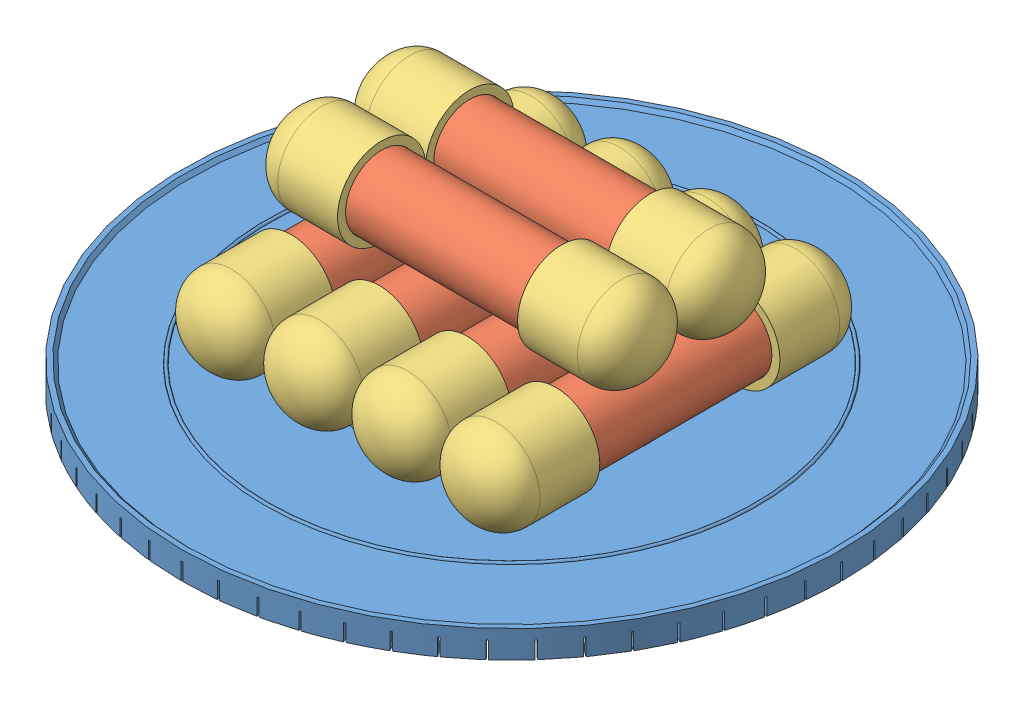
SolidWorks assembly OIL MAT AND SAMPLES, configuration Default. Lengths in mm.
Overall size (307.98 89.57 307.98).
25 component instances, 3 part files, 18 mates.
Components (placement in the parent):
- 5 GALLON LID-1: 5 GALLON LID [Default] at (-59.5528 148.0836 251.4971) size (307.98 12.7 307.98)
- OIL SAMPLE-1: OIL SAMPLE [Default] at (-23.8359 105.1502 145.4945) size (41.17 41.17 172.16)
  - 1 PVC PIPE 14CM-1: 1 PVC PIPE 14CM [48925K93] at (55.8359 74.6326 104.5055) size (33.4 33.4 140)
  - 1 PVC CAP-1: 1 PVC CAP [4880K53] at (55.8359 74.6326 168.5746) x (0 0 1) z (-1 0 0) size (44.02 41.17 41.17)
  - 1 PVC CAP-2: 1 PVC CAP [4880K53] at (55.8359 74.6326 40.4364) x (0 0 -1) z (1 0 0) size (44.02 41.17 41.17)
- OIL SAMPLE-2: OIL SAMPLE [Default] at (17.3375 105.1502 145.4945) size (41.17 41.17 172.16)
  - 1 PVC PIPE 14CM-1: 1 PVC PIPE 14CM [48925K93] at (55.8359 74.6326 104.5055) size (33.4 33.4 140)
  - 1 PVC CAP-1: 1 PVC CAP [4880K53] at (55.8359 74.6326 168.5746) x (0 0 1) z (-1 0 0) size (44.02 41.17 41.17)
  - 1 PVC CAP-2: 1 PVC CAP [4880K53] at (55.8359 74.6326 40.4364) x (0 0 -1) z (1 0 0) size (44.02 41.17 41.17)
- OIL SAMPLE-3: OIL SAMPLE [Default] at (58.5109 105.1502 145.4945) size (41.17 41.17 172.16)
  - 1 PVC PIPE 14CM-1: 1 PVC PIPE 14CM [48925K93] at (55.8359 74.6326 104.5055) size (33.4 33.4 140)
  - 1 PVC CAP-1: 1 PVC CAP [4880K53] at (55.8359 74.6326 168.5746) x (0 0 1) z (-1 0 0) size (44.02 41.17 41.17)
  - 1 PVC CAP-2: 1 PVC CAP [4880K53] at (55.8359 74.6326 40.4364) x (0 0 -1) z (1 0 0) size (44.02 41.17 41.17)
- OIL SAMPLE-4: OIL SAMPLE [Default] at (99.6843 105.1502 145.4945) size (41.17 41.17 172.16)
  - 1 PVC PIPE 14CM-1: 1 PVC PIPE 14CM [48925K93] at (55.8359 74.6326 104.5055) size (33.4 33.4 140)
  - 1 PVC CAP-1: 1 PVC CAP [4880K53] at (55.8359 74.6326 168.5746) x (0 0 1) z (-1 0 0) size (44.02 41.17 41.17)
  - 1 PVC CAP-2: 1 PVC CAP [4880K53] at (55.8359 74.6326 40.4364) x (0 0 -1) z (1 0 0) size (44.02 41.17 41.17)
- OIL SAMPLE-5: OIL SAMPLE [Default] at (-10 142.4374 326.1734) x (0 0 -1) z (1 0 0) size (41.17 41.17 172.16)
  - 1 PVC PIPE 14CM-1: 1 PVC PIPE 14CM [48925K93] at (55.8359 74.6326 104.5055) size (33.4 33.4 140)
  - 1 PVC CAP-1: 1 PVC CAP [4880K53] at (55.8359 74.6326 168.5746) x (0 0 1) z (-1 0 0) size (44.02 41.17 41.17)
  - 1 PVC CAP-2: 1 PVC CAP [4880K53] at (55.8359 74.6326 40.4364) x (0 0 -1) z (1 0 0) size (44.02 41.17 41.17)
- OIL SAMPLE-6: OIL SAMPLE [Default] at (-10 142.4374 285) x (0 0 -1) z (1 0 0) size (41.17 41.17 172.16)
  - 1 PVC PIPE 14CM-1: 1 PVC PIPE 14CM [48925K93] at (55.8359 74.6326 104.5055) size (33.4 33.4 140)
  - 1 PVC CAP-1: 1 PVC CAP [4880K53] at (55.8359 74.6326 168.5746) x (0 0 1) z (-1 0 0) size (44.02 41.17 41.17)
  - 1 PVC CAP-2: 1 PVC CAP [4880K53] at (55.8359 74.6326 40.4364) x (0 0 -1) z (1 0 0) size (44.02 41.17 41.17)
Mates (geometry in assembly coordinates):
- Coincident2: coincident aligned: plane of OIL SAMPLE-1 through (-23.8359 105.1502 145.4945) normal (0 1 0); plane of OIL SAMPLE-2 through (17.3375 105.1502 145.4945) normal (0 1 0)
- Coincident3: coincident aligned: plane of OIL SAMPLE-1 through (-23.8359 105.1502 145.4945) normal (0 1 0); plane of OIL SAMPLE-3 through (58.5109 105.1502 145.4945) normal (0 1 0)
- Coincident4: coincident aligned: plane of OIL SAMPLE-1 through (-23.8359 105.1502 145.4945) normal (0 1 0); plane of OIL SAMPLE-4 through (99.6843 105.1502 145.4945) normal (0 1 0)
- Coincident5: coincident aligned: plane of OIL SAMPLE-1 through (-23.8359 105.1502 145.4945) normal (0 0 1); plane of OIL SAMPLE-2 through (17.3375 105.1502 145.4945) normal (0 0 1)
- Coincident6: coincident aligned: plane of OIL SAMPLE-1 through (-23.8359 105.1502 145.4945) normal (0 0 1); plane of OIL SAMPLE-3 through (58.5109 105.1502 145.4945) normal (0 0 1)
- Coincident7: coincident aligned: plane of OIL SAMPLE-1 through (-23.8359 105.1502 145.4945) normal (0 0 1); plane of OIL SAMPLE-4 through (99.6843 105.1502 145.4945) normal (0 0 1)
- Tangent1: tangent anti-aligned: cylinder of OIL SAMPLE-1/1 PVC CAP-1 through (32 179.7828 292.06) axis (0 0 -1) radius 20.5867; cylinder of OIL SAMPLE-2/1 PVC CAP-1 through (73.1734 179.7828 292.06) axis (0 0 -1) radius 20.5867
- Tangent2: tangent anti-aligned: cylinder of OIL SAMPLE-2/1 PVC CAP-1 through (73.1734 179.7828 292.06) axis (0 0 -1) radius 20.5867; cylinder of OIL SAMPLE-3/1 PVC CAP-1 through (114.3468 179.7828 292.06) axis (0 0 -1) radius 20.5867
- Tangent3: tangent anti-aligned: cylinder of OIL SAMPLE-3/1 PVC CAP-1 through (114.3468 179.7828 292.06) axis (0 0 -1) radius 20.5867; cylinder of OIL SAMPLE-4/1 PVC CAP-1 through (155.5202 179.7828 292.06) axis (0 0 -1) radius 20.5867
- Distance1: distance = 250 mm aligned: plane of OIL SAMPLE-1/1 PVC PIPE 14CM-1 through (32 179.7828 250) normal (0 0 1); plane of assembly through (0 0 0) normal (0 0 1)
- Distance2: distance = 32 mm aligned: plane of assembly through (0 0 0) normal (1 0 0); plane of OIL SAMPLE-1/1 PVC PIPE 14CM-1 through (32 179.7828 250) normal (1 0 0)
- Tangent4: tangent anti-aligned: plane of 5 GALLON LID-1 through (5.5347 159.1961 251.4971) normal (0 1 0); cylinder of OIL SAMPLE-4/1 PVC CAP-2 through (155.5202 179.7828 207.94) axis (0 0 1) radius 20.5867
- Coincident11: coincident aligned: plane of OIL SAMPLE-5; plane of OIL SAMPLE-6
- Coincident12: coincident aligned: plane of OIL SAMPLE-5 through (-10 142.4374 326.1734) normal (1 0 0); plane of OIL SAMPLE-6 through (-10 142.4374 285) normal (1 0 0)
- Tangent5: tangent anti-aligned: cylinder of OIL SAMPLE-5/1 PVC CAP-1 through (136.5655 217.07 270.3375) axis (-1 0 0) radius 20.5867; cylinder of OIL SAMPLE-6/1 PVC CAP-1 through (136.5655 217.07 229.1641) axis (-1 0 0) radius 20.5867
- Distance4: distance = 285 mm anti-aligned: plane of OIL SAMPLE-6 through (-10 142.4374 285) normal (0 0 -1); plane of assembly through (0 0 0) normal (0 0 1)
- Distance5: distance = 10 mm aligned: plane of OIL SAMPLE-6 through (-10 142.4374 285) normal (1 0 0); plane of assembly through (0 0 0) normal (1 0 0)
- Tangent6: tangent anti-aligned: cylinder of OIL SAMPLE-1/1 PVC PIPE 14CM-1 through (32 179.7828 320) axis (0 0 -1) radius 16.7005; cylinder of OIL SAMPLE-5/1 PVC CAP-2 through (52.4455 217.07 270.3375) axis (1 0 0) radius 20.5867
